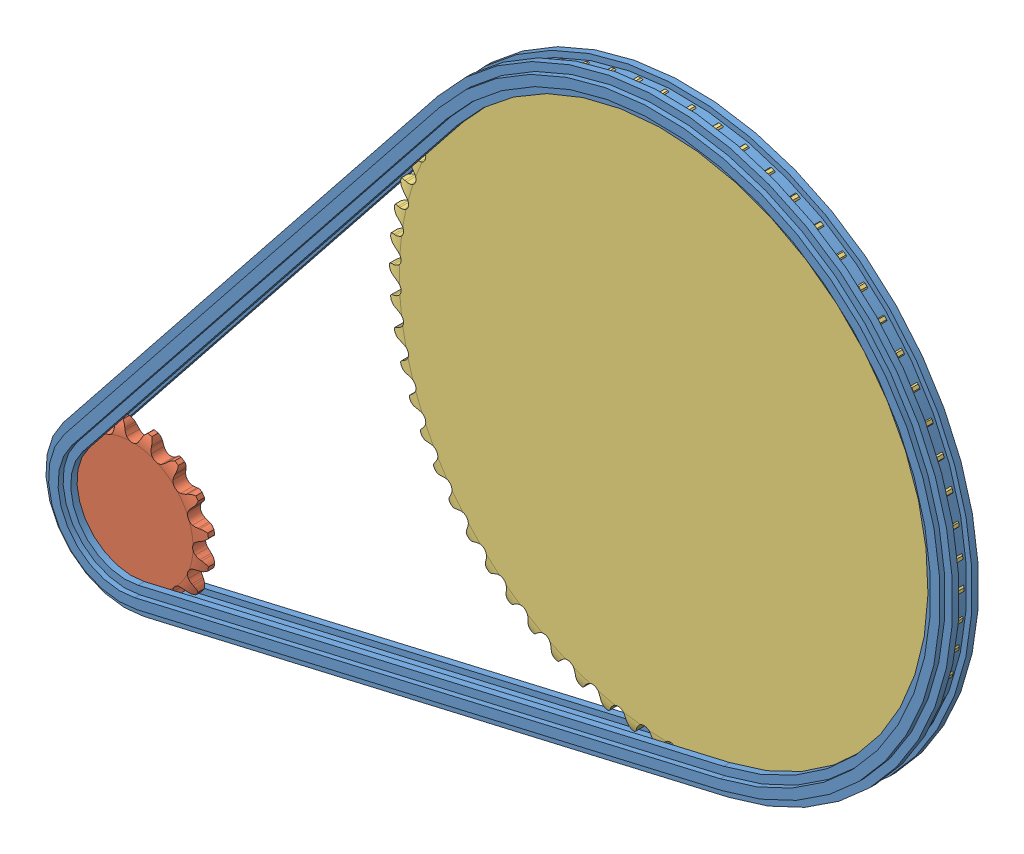
SolidWorks assembly chain drive2, configuration Default. Lengths in mm.
Overall size (218.83 170.94 8.64).
3 component instances, 3 part files, 0 mates.
Components (placement in the parent):
- Roller Chain-1-1: Roller Chain-1 [Default] at (280.5916 -228.011 -328.0371) size (218.83 170.94 8.64)
- Roller Chain Sprocket1-1-1: Roller Chain Sprocket1-1 [Default] at (153.3002 -231.2129 -328.0371) size (35.23 35.23 3.68)
- Roller Chain Sprocket2-1-1: Roller Chain Sprocket2-1 [Default] at (283.1316 -149.271 -328.0371) size (137.11 136.99 3.98)
